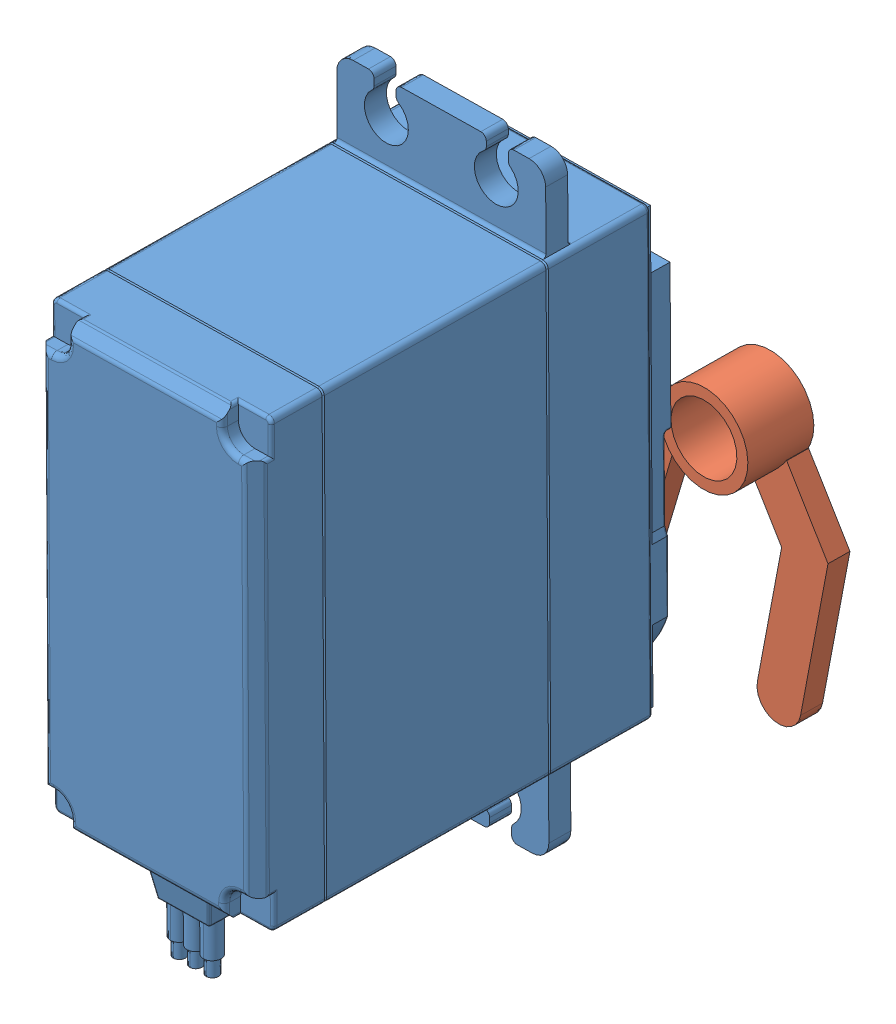
SolidWorks assembly Dropper, configuration Défaut. Lengths in mm.
Overall size (34.82 67.09 56.96).
2 component instances, 2 part files, 3 mates.
Components (placement in the parent):
- MG995 (1)-1: MG995 (1) [Défaut] at (-29.3153 14.7553 109.1659) x (0.016609 -0.999802 0.010927) z (0 -0.010928 -0.99994) size (55.5 20 44.5)
- Pièce2-1: Pièce2 [Défaut] at (-29.1492 4.2032 58.5817) x (0.526861 -0.849901 0.009289) z (0 -0.010928 -0.99994) size (25.29 25.29 6)
Mates (geometry in assembly coordinates):
- Coaxiale1: concentric aligned: circle of Ensamblaje1-1/Pieza2-1; circle of Pièce2-1
- Coïncidente9: coincident anti-aligned: circle of Ensamblaje1-1/Pieza2-1; plane of Pièce2-1 through (-15.0456 28.9424 62.0383) normal (0 0.010928 0.99994)
- Concentric1: concentric aligned: cylinder of MG995 (1)-1 through (-29.1492 4.3256 69.7776) axis (0 0.010928 0.99994) radius 2; cylinder of Pièce2-1 through (-29.1492 4.1376 52.5821) axis (0 0.010928 0.99994) radius 4
